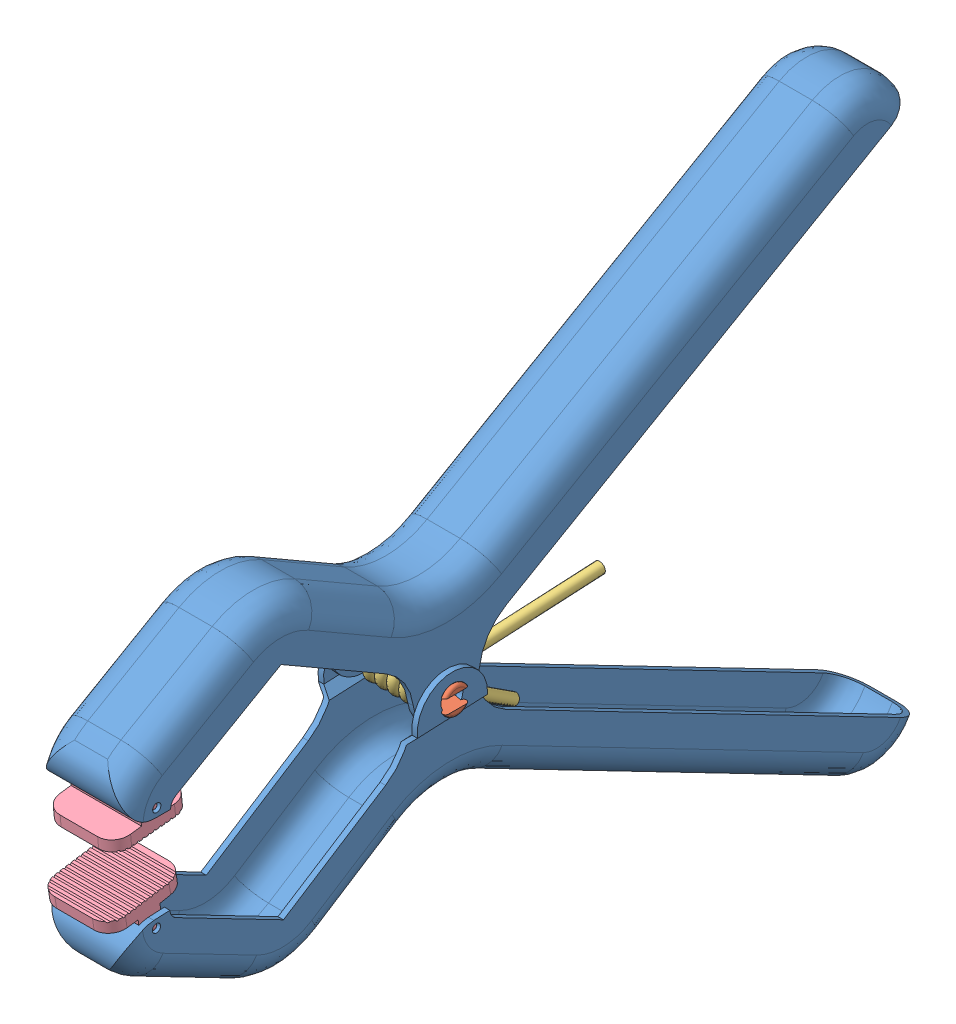
SolidWorks assembly lijmklem assembly, configuration Default. Lengths in mm.
Overall size (19.5 115.59 147.17).
6 component instances, 4 part files, 7 mates.
Components (placement in the parent):
- knijper-1: knijper [15mm] at (14.9582 64.4883 136.792) size (16.76 60.54 142.9)
- knijper-2: knijper [18mm] at (14.9582 27.563 135.9442) x (-1 0 0) z (0 -0.045895 0.998946) size (18 60.54 142.9)
- pin-1: pin [Default] at (5.4565 46.1881 129.292) size (19.5 6 6)
- spiraal veer-1: spiraal veer [Default] at (11.2782 46.1881 129.292) x (0 -0.54484 -0.83854) z (0 -0.83854 0.54484) size (33.68 11.68 23.97)
- knijpgrip tang-1: knijpgrip tang [Default] at (21.4582 35.2876 181.3465) x (0 0.154519 -0.98799) z (-1 0 0) size (14 6.52 14.3)
- knijpgrip tang-2: knijpgrip tang [Default] at (21.9582 54.6881 181.792) x (0 -0.097627 0.995223) z (-1 0 0) size (14 6.52 14.3)
Mates (geometry in assembly coordinates):
- Coincident1: coincident: circle of knijper-1; circle of knijper-2
- Concentric1: concentric: cylinder of knijper-2 through (27.4582 46.1881 129.292) axis (-1 0 0) radius 2; cylinder of pin-1 through (5.4565 46.1881 129.292) axis (-1 0 0) radius 2
- Coincident2: coincident: plane of knijper-2 through (5.9582 43.8519 129.1846) normal (-1 0 0); plane of pin-1 through (5.9582 49.1881 129.292) normal (1 0 0)
- Concentric2: concentric: cylinder of pin-1 through (5.4565 46.1881 129.292) axis (-1 0 0) radius 2; circle of spiraal veer-1
- Tangent2: tangent: plane of knijper-1 through (21.9582 60.1373 159.2557) normal (-1 0 0); cylinder of spiraal veer-1 through (20.9582 50.2476 99.4629) axis (0 -0.052096 0.998642) radius 1
- Coincident4: coincident: circle of knijper-2; circle of knijpgrip tang-1
- Coincident5: coincident: circle of knijper-1; circle of knijpgrip tang-2
